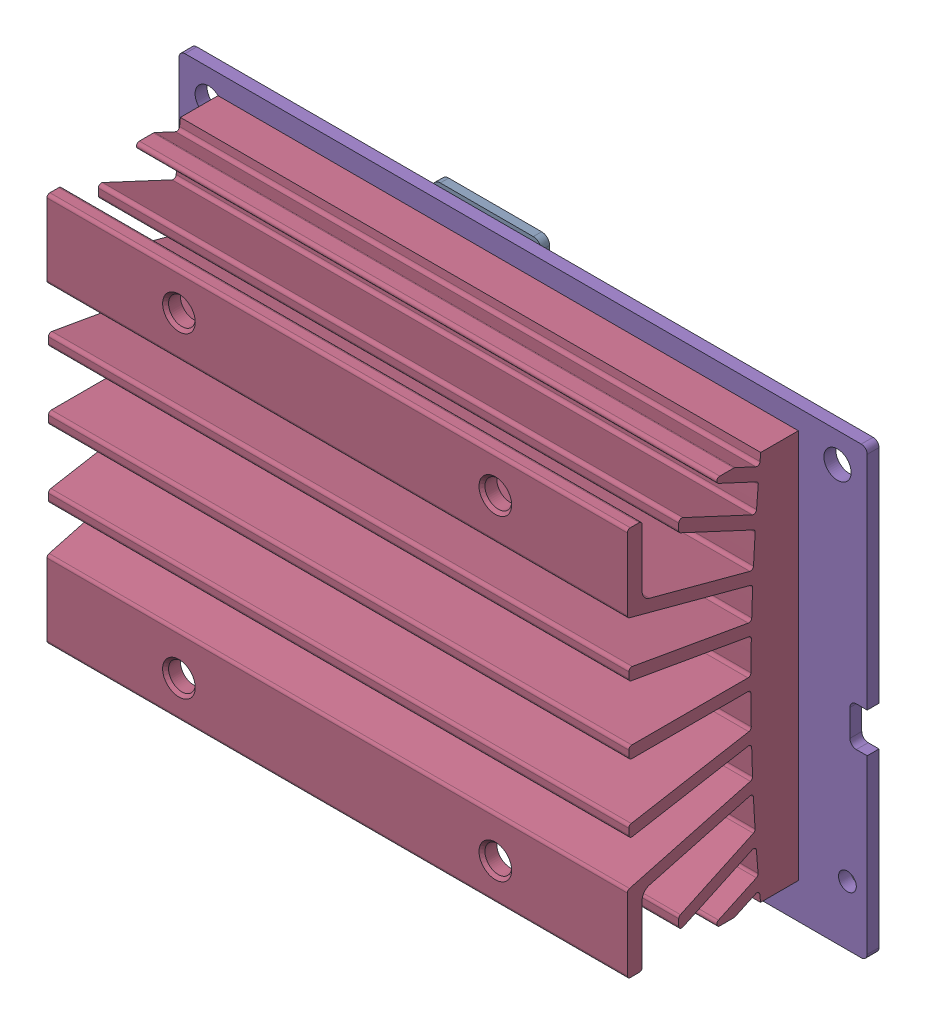
SolidWorks assembly 244-63448-0000-000_ASM.step, configuration Default. Lengths in mm.
Overall size (69.6 45 21.37).
13 component instances, 6 part files, 0 mates.
Components (placement in the parent):
- 142-13448-1000-A02_ASM.step-1: 142-13448-1000-A02_ASM.step [Default] at origin size (23 37.01 4.01)
  - 080-0051-000_3.step-1: 080-0051-000_3.step [Default] at (28.331 29.139 0) x (-1 0 0) z (0 0 -1) size (13.4 17 1.28)
  - TM670M-A2_1.step-1: TM670M-A2_1.step [Default] at (23.7 13.45 1.2) size (23 23 1.29)
- 142-13448-1000-A02-SKU0000_ASM.step-1: 142-13448-1000-A02-SKU0000_ASM.step [Default] at origin size (23 23 1.29)
  - TM670M-A2_1.step-1: TM670M-A2_1.step [Default] at (23.7 13.45 1.2) size (23 23 1.29)
- PORG_HSK_ASSY_ASM.step-1: PORG_HSK_ASSY_ASM.step [Default] at (0 0 4.01) size (58.7 39.4 17.3)
  - PORG_HEAT_SINK.step-1: PORG_HEAT_SINK.step [Default] at origin size (58.7 39.4 17.3)
- 142-63448-1GEN_A00.step-1: 142-63448-1GEN_A00.step [Default] at origin size (69.6 45 1.2)
- PORG_LEAF_SPRING_DRAWN.step-1: PORG_LEAF_SPRING_DRAWN.step [Default] at (0 0 -0.4) x (1 0.000001 0) z (0 0 1) size (39.83 21.3 1.2)
- PORG_LEAF_SPRING_SCREW.step-1: PORG_LEAF_SPRING_SCREW.step [Default] at (6.9871 5.9982 5.21) x (0 0 -1) z (0 1 0) size (6.41 4.7 4.7)
- PORG_LEAF_SPRING_SCREW.step-2: PORG_LEAF_SPRING_SCREW.step [Default] at (6.9871 20.9018 5.21) x (0 0 -1) z (0 1 0) size (6.41 4.7 4.7)
- PORG_LEAF_SPRING_SCREW.step-3: PORG_LEAF_SPRING_SCREW.step [Default] at (40.4129 20.9018 5.21) x (0 0 -1) z (0 1 0) size (6.41 4.7 4.7)
- PORG_LEAF_SPRING_SCREW.step-4: PORG_LEAF_SPRING_SCREW.step [Default] at (40.4129 5.9982 5.21) x (0 0 -1) z (0 1 0) size (6.41 4.7 4.7)
